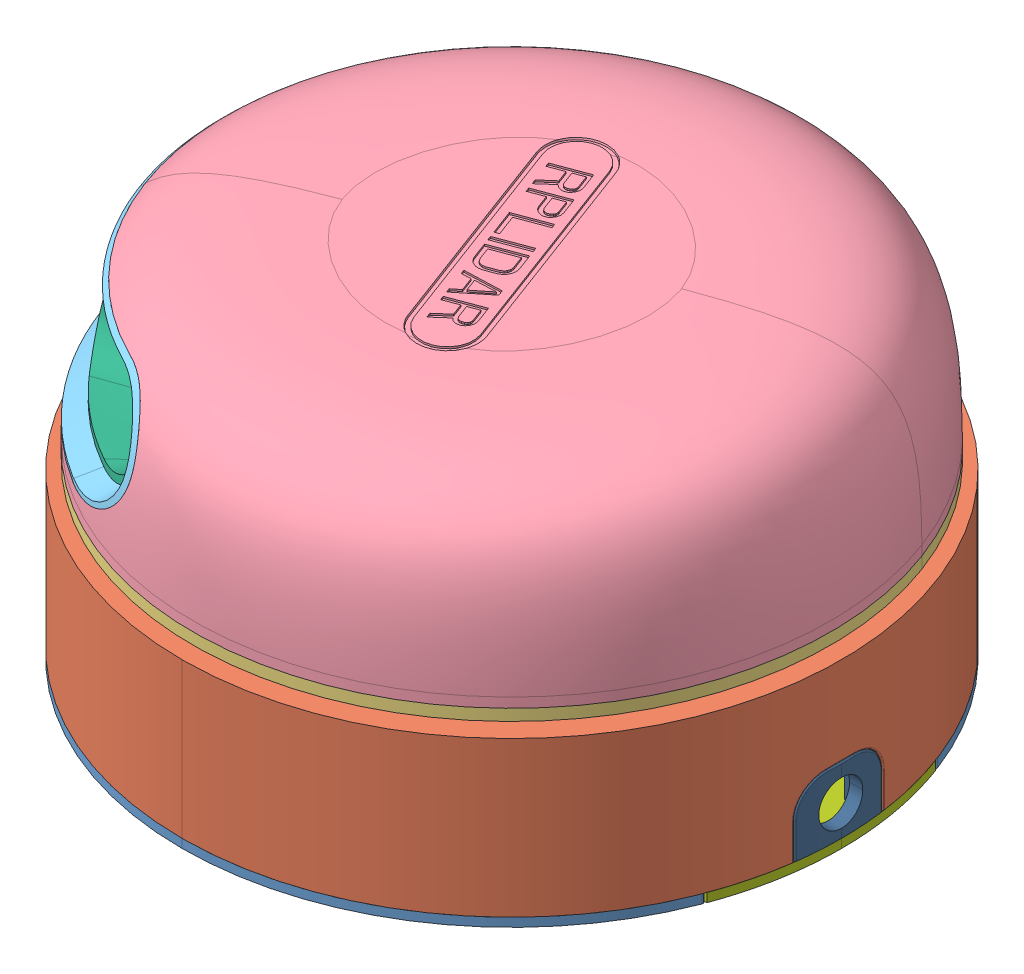
SolidWorks assembly rplidar-a2m4-r1, configuration Default. Lengths in mm.
Overall size (101.21 40.81 93.31).
18 component instances, 15 part files, 0 mates.
Components (placement in the parent):
- rplidar-a2m4-r1.igs-1: rplidar-a2m4-r1.igs [Default] at origin size (153.23 40.81 93.31)
  - RPLIDAR A2.igs-1: RPLIDAR A2.igs [Default] at origin size (153.23 40.81 93.31)
    - µ×¸Ç.igs-1: µ×¸Ç.igs [Default] at (-6.0269 8.2139 75) size (72.54 3.5 75)
    - ±àÂë³ÝÍâ¿Ç.igs-1: ±àÂë³ÝÍâ¿Ç.igs [Default] at (-6.0269 21.5139 75) size (75 18.2 75)
    - Ðý×ªÆ½Ì¨.igs-1: Ðý×ªÆ½Ì¨.igs [Default] at (-6.0269 28.0139 75) x (-0.350209 0 -0.936671) z (0.936671 0 -0.350209) size (72.5 4 72.5)
    - LENS_1.6.igs-1: LENS_1.6.igs [Default] at (-6.0269 21.5139 75) x (0.350209 0 0.936671) z (-0.936671 0 0.350209) size (72.5 20.11 72.51)
    - KEY_1.6.igs-1: KEY_1.6.igs [Default] at (-6.0269 21.5139 75) x (0.350209 0 0.936671) z (-0.936671 0 0.350209) size (60.14 14.28 48.82)
    - BAT_COVER_19.igs-1: BAT_COVER_19.igs [Default] at (-6.0269 21.5139 75) x (0.350209 0 0.936671) z (-0.936671 0 0.350209) size (56.96 17.71 24.64)
    - ·â¸Ç.igs-1: ·â¸Ç.igs [Default] at (-6.0269 9.7139 75) x (0 0 -1) z (-1 0 0) size (26 1.5 12.5)
    - ¼¤¹â·¢ÉäÍ·.igs-1: ¼¤¹â·¢ÉäÍ·.igs [Default] at (-8.2841 39.0139 48.9161) x (0.148651 0.950235 0.273781) z (-0.878816 0 0.477161) size (6 6 21.2)
    - ¾µÍ·.igs-1: ¾µÍ·.igs [Default] at (-10.3767 39.0139 94.7757) x (0.331722 0.320609 0.887226) z (-0.936671 0 0.350209) size (14 14 11.5)
    - Íâ½ÓÏßÕûÌå.igs-1: Íâ½ÓÏßÕûÌå.igs [Default] at (63.3713 -12.8505 75) size (86.12 10.5 15.7)
      - 4pinÏßÀÂ.igs-1: 4pinÏßÀÂ.igs [Default] at (-33.3982 25.5643 0) size (47.5 6.01 9.06) (hidden)
      - ½ÓÏß¶Ë¸Ç.igs-1: ½ÓÏß¶Ë¸Ç.igs [Default] at (-69.3982 22.0643 0) x (0 0 1) z (-1 0 0) size (15 10.5 3.84)
      - 6p ²åÍ·.igs-1: 6p ²åÍ·.igs [Default] at (-51.3982 24.9643 0) x (0 0 1) z (-1 0 0) size (13.7 5 6.45)
      - Áã¼þ4^Íâ½ÓÏßÕûÌå.igs-1: Áã¼þ4^Íâ½ÓÏßÕûÌå.igs [Default] at (-35.3982 25.5643 0) x (0 0 1) z (-1 0 0) size (11.96 4.71 15.01)
      - 5pin 2.54²åÍ·.igs-1: 5pin 2.54²åÍ·.igs [Default] at (22.0731 25.0643 -0.6) x (1 0 0) z (0 0 -1) size (8 5.5 15.2) (hidden)
      - Áã¼þ1^Íâ½ÓÏßÕûÌå.igs-1: Áã¼þ1^Íâ½ÓÏßÕûÌå.igs [Default] at (22.0731 25.0643 -0.6) x (0 0 -1) z (-1 0 0) size (12.22 4.98 9.98) (hidden)
